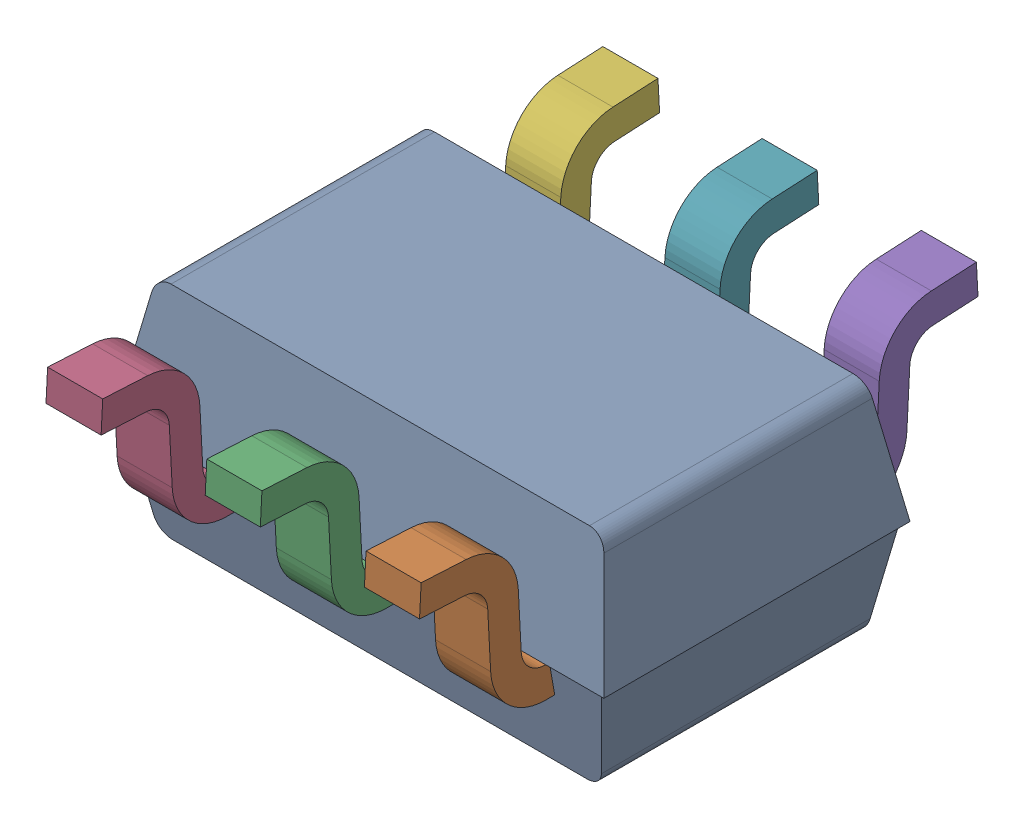
SolidWorks assembly DCK0006A, configuration Default. Lengths in mm.
Overall size (2 0.95 2.28).
8 component instances, 7 part files, 0 mates.
Components (placement in the parent):
- DCK0006A_2-1: DCK0006A_2 [Default] at origin size (2 0.9 1.25)
- DCK0006A_1-1: DCK0006A_1 [Default] at (0.65 0 0) x (0 0 1) z (1 0 0) size (2.28 0.67 1.53)
  - DCK0006A_3-1: DCK0006A_3 [Default] at origin size (0.55 0.67 0.23)
  - DCK0006A_4-1: DCK0006A_4 [Default] at origin size (0.55 0.67 0.23)
  - DCK0006A_5-1: DCK0006A_5 [Default] at origin size (0.55 0.67 0.23)
  - DCK0006A_6-1: DCK0006A_6 [Default] at origin size (0.55 0.67 0.23)
  - DCK0006A_7-1: DCK0006A_7 [Default] at origin size (0.55 0.67 0.23)
  - DCK0006A_8-1: DCK0006A_8 [Default] at origin size (0.55 0.67 0.23)
